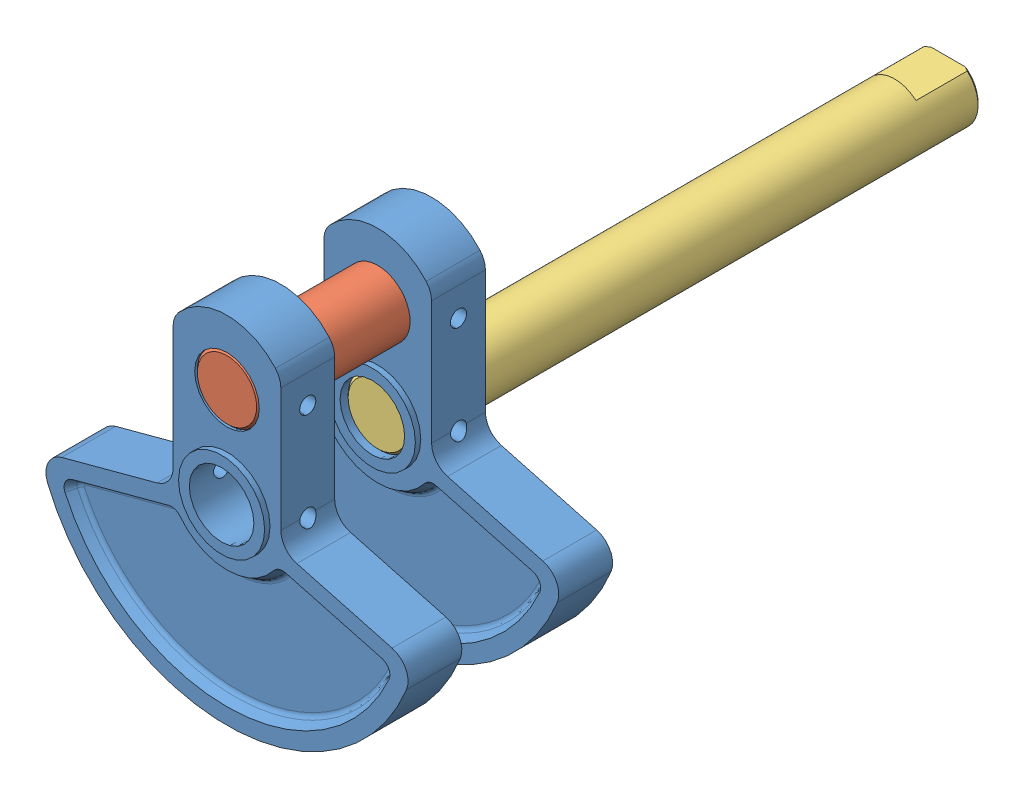
SolidWorks assembly Crankshaft Assembly, configuration Default. Lengths in mm.
Overall size (67.26 66 135).
4 component instances, 3 part files, 7 mates.
Components (placement in the parent):
- 16.Crankshaft Counterweight-1: 16.Crankshaft Counterweight [Default] at (28.5569 44.3424 45.571) size (67.26 66 12)
- 18.Crankshaft Pin-1: 18.Crankshaft Pin [Default] at (28.5569 62.3424 78.571) size (12 12 38)
- 16.Crankshaft Counterweight-2: 16.Crankshaft Counterweight [Default] at (28.5569 44.3424 73.571) size (67.26 66 12)
- 17.Crankshaft-1: 17.Crankshaft [Default] at (28.5569 44.3424 50.571) x (-1 0 0) z (0 0 -1) size (12 12 106)
Mates (geometry in assembly coordinates):
- Concentric1: concentric anti-aligned: cylinder of 16.Crankshaft Counterweight-1 through (28.5569 62.3424 50.571) axis (0 0 -1) radius 6; cylinder of 18.Crankshaft Pin-1 through (28.5569 62.3424 40.571) axis (0 0 1) radius 6
- Concentric2: concentric anti-aligned: cylinder of 18.Crankshaft Pin-1 through (28.5569 62.3424 40.571) axis (0 0 1) radius 6; cylinder of 16.Crankshaft Counterweight-2 through (28.5569 62.3424 78.571) axis (0 0 -1) radius 6
- Coincident1: coincident aligned: plane of 16.Crankshaft Counterweight-1 through (22.5569 67.6339 40.571) normal (0 0 -1); plane of 18.Crankshaft Pin-1 through (28.5569 62.3424 40.571) normal (0 0 -1)
- Coincident2: coincident aligned: plane of 18.Crankshaft Pin-1 through (28.5569 62.3424 78.571) normal (0 0 1); plane of 16.Crankshaft Counterweight-2 through (22.5569 67.6339 78.571) normal (0 0 1)
- Concentric3: concentric: cylinder of 16.Crankshaft Counterweight-1 through (28.5569 44.3424 50.571) axis (0 0 -1) radius 6; cylinder of 17.Crankshaft-1 through (28.5569 44.3424 -55.8874) axis (0 0 1) radius 6
- Concentric4: concentric anti-aligned: cylinder of 16.Crankshaft Counterweight-1 through (62.1888 62.3424 45.571) axis (-1 0 0) radius 1.5; cylinder of 18.Crankshaft Pin-1 through (22.5569 62.3424 45.571) axis (1 0 0) radius 1.5
- Concentric5: concentric aligned: cylinder of 16.Crankshaft Counterweight-1 through (62.1888 44.3424 45.571) axis (-1 0 0) radius 1.5; cylinder of 17.Crankshaft-1 through (34.5569 44.3424 45.571) axis (-1 0 0) radius 1.5
